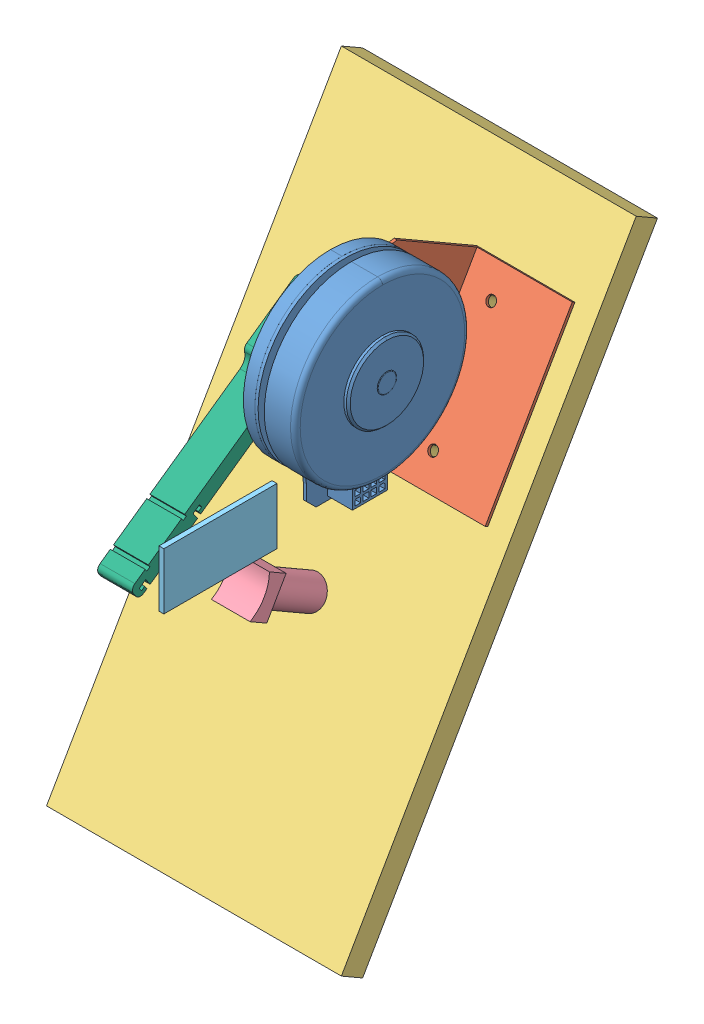
SolidWorks assembly Assembly, configuration Default. Lengths in mm.
Overall size (152.4 285.76 228.14).
6 component instances, 6 part files, 11 mates.
Components (placement in the parent):
- 323772_EC90fl_90W_A.stp-1: 323772_EC90fl_90W_A.stp [Default] at (-12.0706 17.4335 -1.827) size (54.6 104 90)
- Part2-1: Part2 [Default] at (-13.6581 24.844 -78.9916) x (0 -0.866025 0.5) z (-1 0 0) size (90 99.82 50.8)
- base Plate-1: base Plate [Default] at (-103.4706 -211.0027 42.5099) x (0 0.866025 -0.5) z (1 0 0) size (304.8 12.7 152.4)
- finger rest-1: finger rest [Default] at (-37.2706 -93.6022 25.8536) x (0 0.866025 -0.5) z (1 0 0) size (20 65 20)
- Part1-1: Part1 [Default] at (19.3807 5.5265 118.2456) size (2.54 29.21 58.42)
- moment beam shortened-1: moment beam shortened [Default] at (-19.2706 17.4335 -1.827) x (0 -0.575905 0.817517) z (-1 0 0) size (132.5 20 19)
Mates (geometry in assembly coordinates):
- Coincident1: coincident anti-aligned: plane of Part2-1 through (-13.6581 -53.0983 -33.9916) normal (0 -0.5 -0.866025); plane of base Plate-1 through (-103.4706 -204.6527 53.5084) normal (0 0.5 0.866025)
- Concentric1: concentric aligned: cylinder of 323772_EC90fl_90W_A.stp-1 through (2.4843 -6.5665 -1.827) axis (-1 0 0) radius 2.1; circle of Part2-1
- Parallel2: parallel anti-aligned: line of Part2-1 through (37.1419 -52.3045 -32.6168) axis (0 0.866025 -0.5); line of base Plate-1 through (-103.4706 59.3118 -98.8916) axis (0 -0.866025 0.5)
- Coincident7: coincident anti-aligned: plane of 323772_EC90fl_90W_A.stp-1 through (-12.0706 17.4335 -1.827) normal (-1 0 0); plane of Part2-1 through (-12.0706 -52.3045 -32.6168) normal (1 0 0)
- Concentric2: concentric aligned: circle of 323772_EC90fl_90W_A.stp-1; circle of Part2-1
- Parallel5: parallel anti-aligned: plane of base Plate-1 through (-103.4706 -204.6527 53.5084) normal (0 0.5 0.866025); plane of finger rest-1 through (-27.2706 -112.4419 -26.7778) normal (0 -0.5 -0.866025)
- Parallel7: parallel anti-aligned: line of base Plate-1 through (-103.4706 59.3118 -98.8916) axis (0 -0.866025 0.5); line of finger rest-1 through (-17.2706 -93.6022 25.8536) axis (0 0.866025 -0.5)
- Concentric9: concentric anti-aligned: circle of Part2-1; circle of base Plate-1
- Concentric10: concentric anti-aligned: circle of base Plate-1; circle of finger rest-1
- Concentric11: concentric anti-aligned: cylinder of 323772_EC90fl_90W_A.stp-1 through (20.0594 17.4335 -1.827) axis (-1 0 0) radius 5; cylinder of moment beam shortened-1 through (-37.2706 17.4335 -1.827) axis (1 0 0) radius 5.05
- Coincident8: coincident aligned: plane of 323772_EC90fl_90W_A.stp-1 through (-37.2706 17.4335 -1.827) normal (-1 0 0); plane of moment beam shortened-1 through (-37.2706 17.4335 -1.827) normal (-1 0 0)
